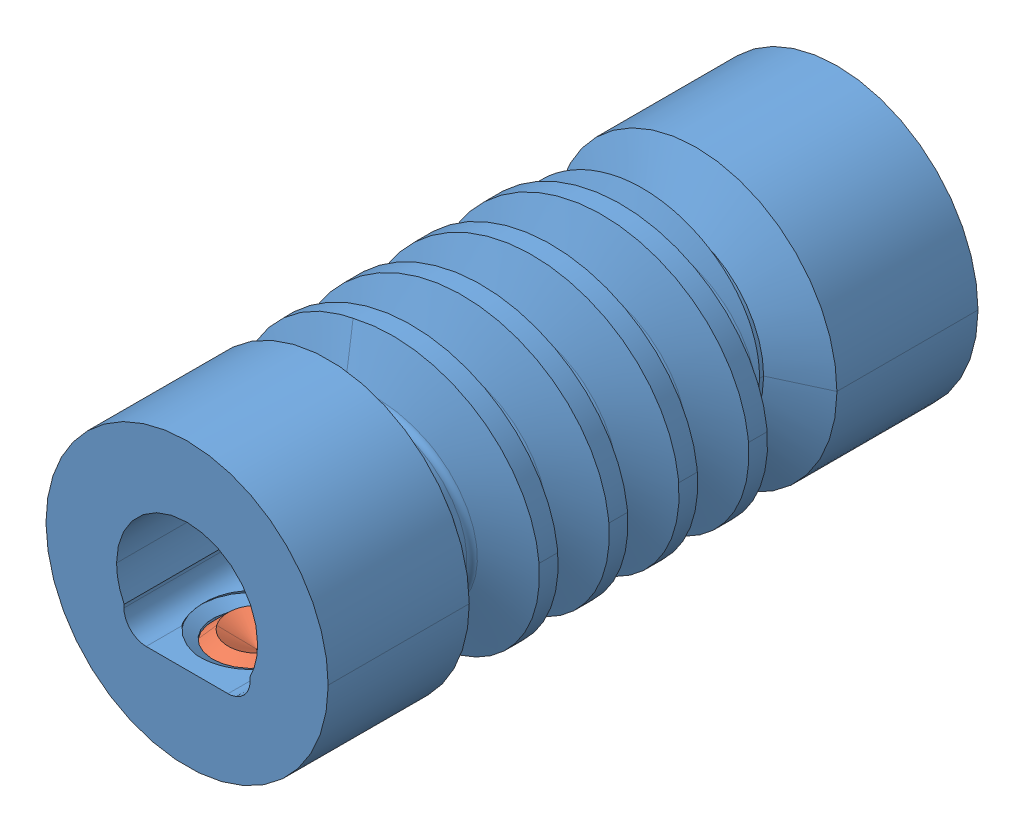
SolidWorks assembly 615462 assembly, configuration Default. Lengths in mm.
Overall size (12.7 13.35 29.62).
4 component instances, 2 part files, 0 mates.
Components (placement in the parent):
- 615462 assembly.STEP-1: 615462 assembly.STEP [Default] at origin size (12.7 13.35 29.62)
  - 615462.STEP-1: 615462.STEP [Default] at (-12.1392 4.7088 3.3043) size (12.7 13.35 29.25)
  - 632134_91375A436.STEP-1: 632134_91375A436.STEP [Default] at (-12.1392 0.1384 14.7533) x (0.578664 0 0.815566) z (0 -1 0) size (4.83 4.83 3.18)
  - 632134_91375A436.STEP-2: 632134_91375A436.STEP [Default] at (-12.1392 0.1384 -8.1448) x (-0.562691 0 -0.826667) z (0 -1 0) size (4.83 4.83 3.18)
